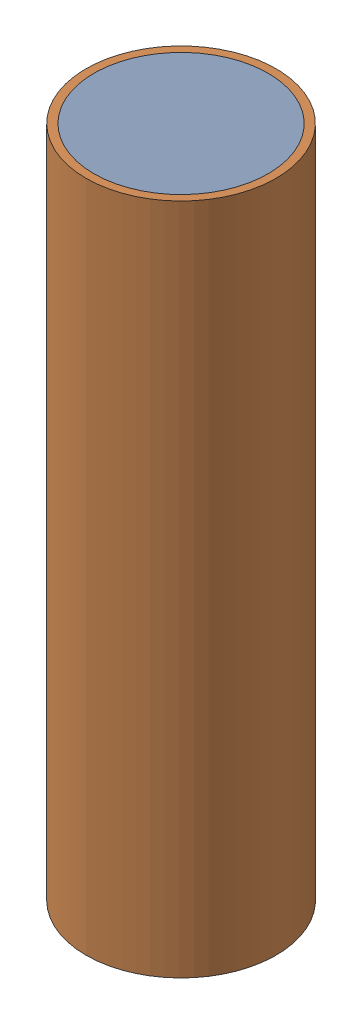
SolidWorks assembly fuel with shielding, configuration Default. Lengths in mm.
Overall size (24 85 24).
2 component instances, 2 part files, 2 mates.
Components (placement in the parent):
- fuel-1: fuel [Default] at origin size (22 85 22)
- fuel shielding-1: fuel shielding [Default] at origin size (24 85 24)
Mates (geometry in assembly coordinates):
- Concentric1: concentric: cylinder of fuel-1 through (0 85 0) axis (0 -1 0) radius 11; cylinder of fuel shielding-1 through (0 85 0) axis (0 -1 0) radius 11
- Coincident1: coincident aligned: plane of fuel-1 through (0 85 0) normal (0 1 0); plane of fuel shielding-1 through (0 85 0) normal (0 1 0)
